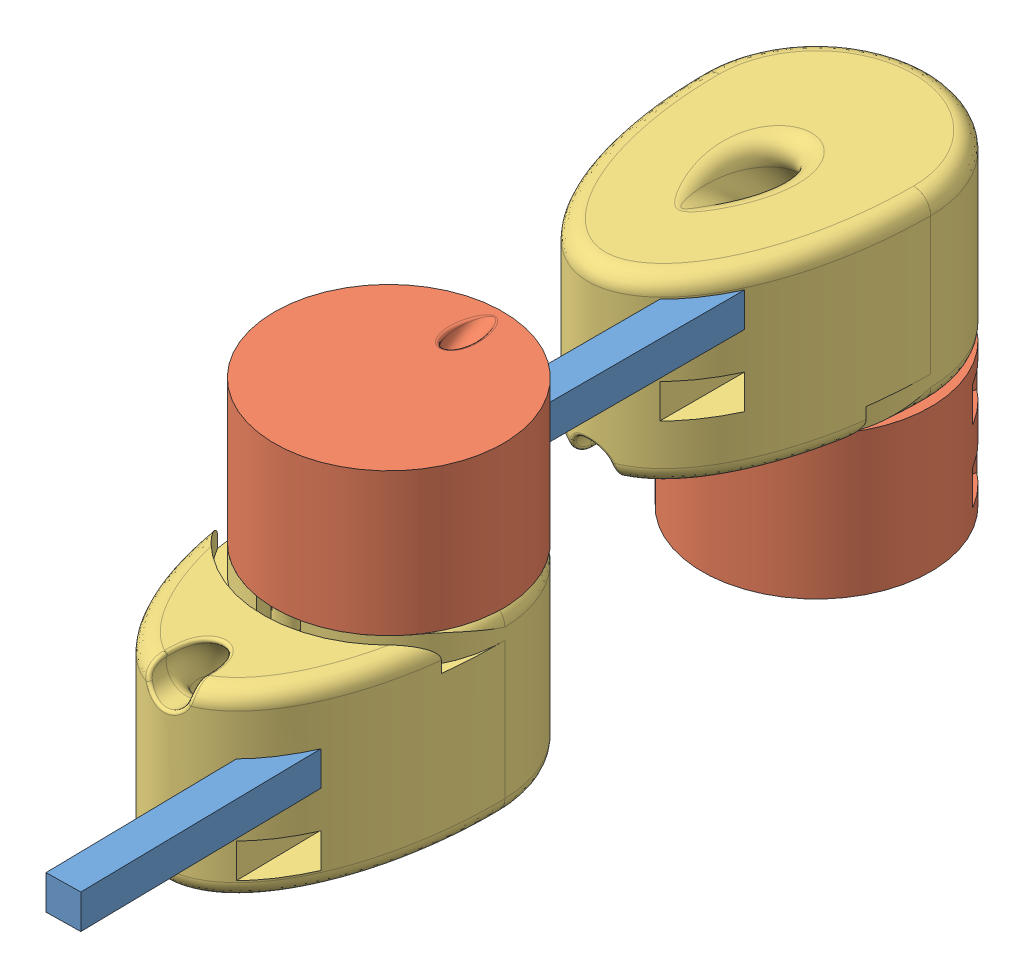
SolidWorks assembly Assem1, configuration Default. Lengths in mm.
Overall size (47.79 70.79 168.74).
6 component instances, 3 part files, 13 mates.
Components (placement in the parent):
- armlink_large-1: armlink_large [Default] at (-18.6542 31.6215 29.3152) size (6 6 50)
- inner_bearing_joint-1: inner_bearing_joint [Default] at (-30.1942 5.9215 84.3152) x (0 0 -1) z (1 0 0) size (40 35.78 40)
- outer_bearing_joint-1: outer_bearing_joint [Default] at (-30.2957 12.93 9.3152) x (0 0 1) z (-1 0 0) size (62.28 40.92 44.83)
- armlink_large-2: armlink_large [Default] at (-18.2193 -0.309 104.1174) x (0.99986 0 -0.016749) z (0.016749 0 0.99986) size (6 6 50)
- inner_bearing_joint-2: inner_bearing_joint [Default] at (-30.2957 12.93 9.3152) x (0.219146 0 -0.975692) z (-0.975692 0 -0.219146) size (40 35.78 40)
- outer_bearing_joint-2: outer_bearing_joint [Default] at (-30.1942 5.9215 84.3152) x (0.016749 0 0.99986) z (0.99986 0 -0.016749) size (62.28 40.92 44.83)
Mates (geometry in assembly coordinates):
- Coincident4: coincident anti-aligned: plane of armlink_large-1 through (-18.6542 31.6215 79.3152) normal (0 0 1); plane of inner_bearing_joint-1 through (-30.1942 5.9215 79.3152) normal (0 0 -1)
- Coincident5: coincident anti-aligned: plane of armlink_large-1 through (-21.6542 34.6215 79.3152) normal (0 1 0); plane of inner_bearing_joint-1 through (-21.6542 34.6215 54.3152) normal (0 -1 0)
- Coincident6: coincident anti-aligned: plane of armlink_large-1 through (-21.6542 34.6215 79.3152) normal (-1 0 0); plane of inner_bearing_joint-1 through (-21.6542 34.6215 54.3152) normal (1 0 0)
- Coincident7: coincident anti-aligned: plane of armlink_large-1 through (-21.6542 34.6215 79.3152) normal (-1 0 0); plane of outer_bearing_joint-1 through (-21.6542 34.6215 51.5935) normal (1 0 0)
- Coincident8: coincident anti-aligned: plane of armlink_large-1 through (-21.6542 28.6215 79.3152) normal (0 -1 0); plane of outer_bearing_joint-1 through (-21.6542 28.6215 51.5935) normal (0 1 0)
- Coincident9: coincident anti-aligned: plane of armlink_large-1 through (-18.6542 31.6215 29.3152) normal (0 0 -1); plane of outer_bearing_joint-1 through (-30.2957 12.93 29.3152) normal (0 0 1)
- Coincident11: coincident anti-aligned: plane of inner_bearing_joint-1 through (-30.1942 12.9215 84.3152) normal (0 -1 0); plane of outer_bearing_joint-2 through (-30.1942 12.9215 84.3152) normal (0 1 0)
- Concentric1: concentric anti-aligned: circle of inner_bearing_joint-1; circle of outer_bearing_joint-2
- Coincident13: coincident anti-aligned: plane of armlink_large-2 through (-20.3814 2.691 154.1607) normal (-0.99986 0 0.016749); plane of outer_bearing_joint-2 through (-20.8457 2.691 126.4428) normal (0.99986 0 -0.016749)
- Coincident14: coincident anti-aligned: plane of armlink_large-2 through (-20.3814 -3.309 154.1607) normal (0 -1 0); plane of outer_bearing_joint-2 through (-20.8457 -3.309 126.4428) normal (0 1 0)
- Coincident15: coincident anti-aligned: plane of armlink_large-2 through (-18.2193 -0.309 104.1174) normal (-0.016749 0 -0.99986); plane of outer_bearing_joint-2 through (-29.8592 5.9215 104.3124) normal (0.016749 0 0.99986)
- Coincident16: coincident anti-aligned: plane of outer_bearing_joint-1 through (-30.2957 5.93 9.3152) normal (0 -1 0); plane of inner_bearing_joint-2 through (-30.2957 5.93 9.3152) normal (0 1 0)
- Concentric2: concentric anti-aligned: circle of outer_bearing_joint-1; circle of inner_bearing_joint-2
